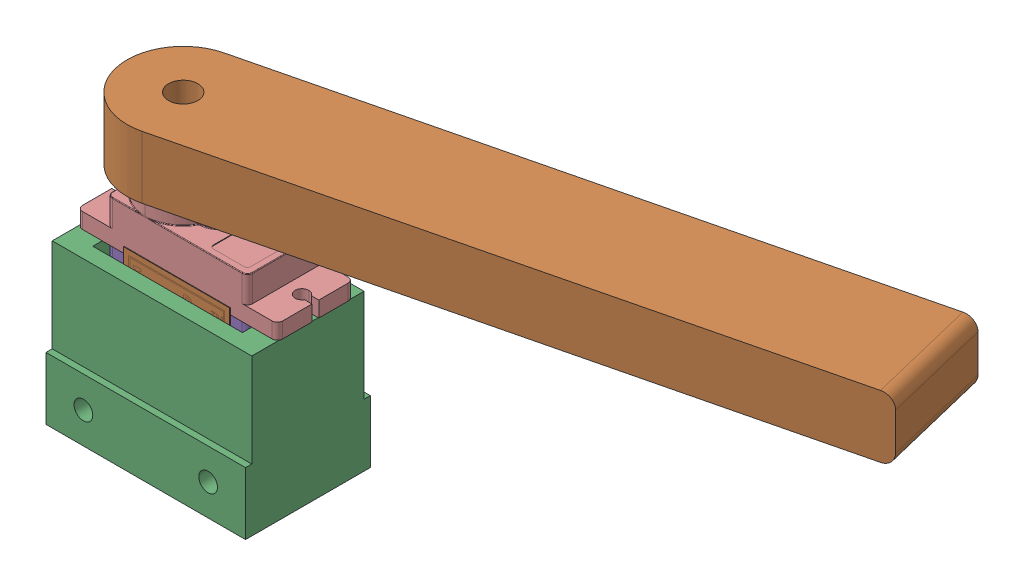
SolidWorks assembly Assemblage_Pic_Panneau_Solaire, configuration Défaut. Lengths in mm.
Overall size (110.88 46.75 43.32).
3 component instances, 3 part files, 5 mates.
Components (placement in the parent):
- Servo_SG90-1: Servo_SG90 [Défaut] at (-12.8661 -23.9295 0) size (32.1 29.95 12.4)
- Bras_Panneau_Solaire-1: Bras_Panneau_Solaire [Défaut] at (-11.3428 9.0882 27.7832) x (0.971503 0 -0.237028) z (0 1 0) size (109 18 10)
- Support_Servo-1: Support_Servo [Défaut] at (-6.9428 -27.6618 28.1832) x (1 0 0) z (0 1 0) size (32 20 25)
Mates (geometry in assembly coordinates):
- Coaxiale1: concentric anti-aligned: circle of Servo_SG90-1; cylinder of bras_panneau_solaire-1 through (-11.3428 19.0882 27.7832) axis (0 -1 0) radius 2.5
- Coïncidente1: coincident anti-aligned: plane of Servo_SG90-1 through (-11.3428 9.0882 27.7832) normal (0 1 0); plane of bras_panneau_solaire-1 through (-11.3428 9.0882 27.7832) normal (0 -1 0)
- Coïncidente2: coincident anti-aligned: plane of Servo_SG90-1 through (-16.5928 -17.6618 33.0332) normal (0 -1 0); plane of Support Servo-1 through (-6.9428 -17.6618 28.1832) normal (0 1 0)
- Coïncidente3: coincident anti-aligned: plane of Servo_SG90-1 through (-16.5928 -1.9618 21.6832) normal (0 0 -1); plane of Support Servo-1 through (-18.9428 -2.6618 21.6832) normal (0 0 1)
- Coïncidente5: coincident anti-aligned: plane of Servo_SG90-1 through (5.0572 -1.9618 33.0332) normal (1 0 0); plane of Support Servo-1 through (5.0572 -2.6618 21.6832) normal (-1 0 0)
